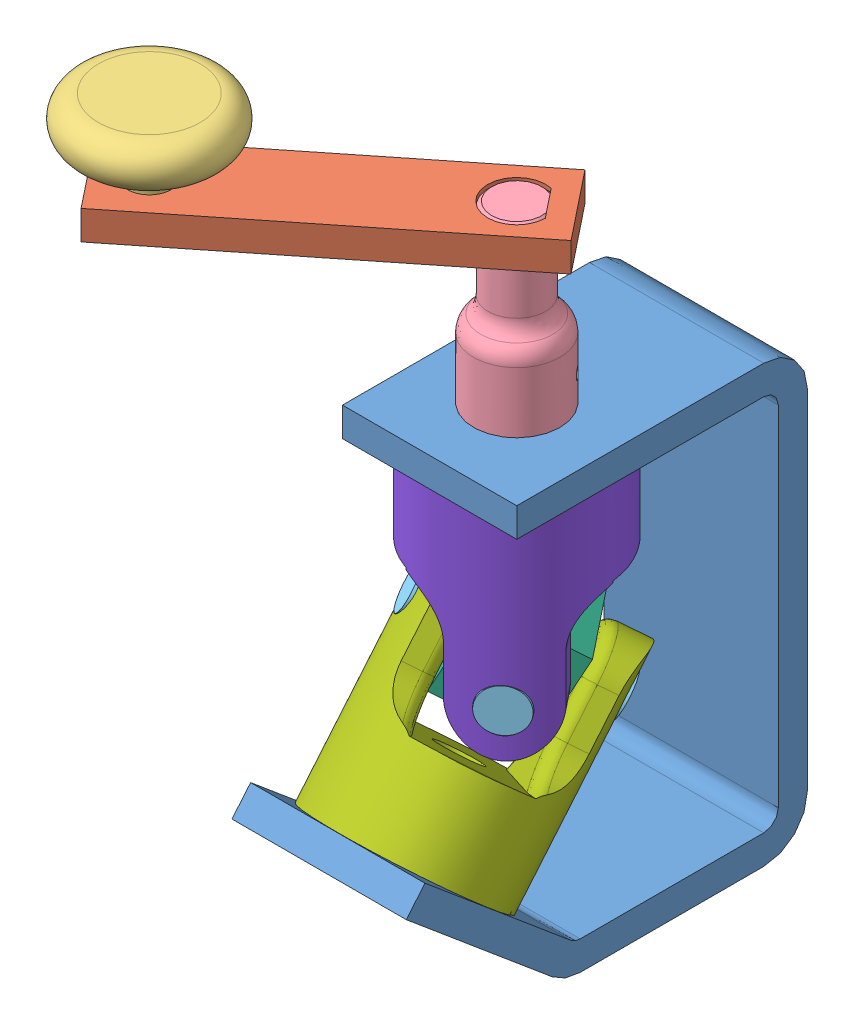
SolidWorks assembly Złożenie1, configuration Domyślna. Lengths in mm.
Overall size (90.07 149.72 98.46).
10 component instances, 8 part files, 21 mates.
Components (placement in the parent):
- bracket-1: bracket [Default] at origin size (38.1 95.25 87.65)
- crank-arm-1: crank-arm [Default] at (-58.0994 121.15 72.1697) x (0.782417 0 -0.622755) z (0.622755 0 0.782417) size (76.2 6.35 19.05)
- crank-knob-1: crank-knob [Default] at (-44.7151 121.15 73.6904) x (0.984418 0 0.175846) z (-0.175846 0 0.984418) size (31.75 22.23 31.75)
- crank-shaft-1: crank-shaft [Default] at (0 89.4 38.1) x (0.782417 0 -0.622755) z (0.622755 0 0.782417) size (18.92 38.1 18.92)
- pin-1: pin [SHORT] at (-3.9545 44.45 33.1317) x (-0.728779 -0.363881 0.580062) z (-0.622755 0 -0.782417) size (9.4 9.4 12.7)
- spider-4: spider [Default] at (0 44.45 38.1) x (-0.693447 0.463133 0.551941) z (-0.622755 0 -0.782417) size (19.05 19.05 19.05)
- Yoke_female-1: Yoke_female [Default] at (0 51.7466 31.9774) x (0.720507 0.445739 0.531211) z (0.693447 -0.463133 -0.551941) size (38.1 47.62 38.1)
- Yoke_male-1: Yoke_male [Default] at (0 34.925 38.1) x (0.782417 0 -0.622755) z (0.622755 0 0.782417) size (38.1 66.67 38.1)
- pin-2: pin [LONG] at (13.2102 35.6273 27.5855) x (0.70373 0.271013 0.656746) z (-0.693447 0.463133 0.551941) size (9.4 9.4 38.1)
- pin-3: pin [SHORT] at (3.9545 44.45 43.0683) x (0.692243 -0.466067 -0.550982) z (0.622755 0 0.782417) size (9.4 9.4 12.7)
Mates (geometry in assembly coordinates):
- Koncentryczne1: concentric anti-aligned: cylinder of crank-arm-1 through (-44.7151 121.15 73.6904) axis (0 1 0) radius 2.3813; cylinder of crank-knob-1 through (-44.7151 121.15 73.6904) axis (0 -1 0) radius 2.286
- Wspólnie1: coincident anti-aligned: plane of crank-arm-1 through (13.3843 127.5 39.6208) normal (0 1 0); plane of crank-knob-1 through (-40.0268 127.5 74.5279) normal (0 -1 0)
- Koncentryczne2: concentric anti-aligned: cylinder of crank-arm-1 through (0 121.15 38.1) axis (0 1 0) radius 6.35; cylinder of crank-shaft-1 through (0 127.5 38.1) axis (0 -1 0) radius 6.2865
- Wspólnie2: coincident anti-aligned: plane of crank-arm-1 through (1.3025 121.15 31.885) normal (-0.782417 0 0.622755); plane of crank-shaft-1 through (6.2863 121.15 38.1466) normal (0.782417 0 -0.622755)
- Wspólnie3: coincident aligned: plane of crank-arm-1 through (13.3843 127.5 39.6208) normal (0 1 0); plane of crank-shaft-1 through (0 127.5 38.1) normal (0 1 0)
- Koncentryczne3: concentric anti-aligned: cylinder of bracket-1 through (0 -6.351 38.1) axis (0 1 0) radius 6.35; cylinder of Yoke_male-1 through (0 101.6 38.1) axis (0 -1 0) radius 6.35
- Wspólnie4: coincident anti-aligned: plane of bracket-1 through (19.05 82.55 3.175) normal (0 -1 0); plane of Yoke_male-1 through (0 82.55 38.1) normal (0 1 0)
- Koncentryczne4: concentric aligned: cylinder of crank-shaft-1 through (0 102.1 38.1) axis (0 -1 0) radius 6.477; cylinder of Yoke_male-1 through (0 101.6 38.1) axis (0 -1 0) radius 6.35
- Równolegle2: parallel anti-aligned: plane of crank-shaft-1 through (6.471 102.1 38.3786) normal (-0.782417 0 0.622755); plane of Yoke_male-1 through (6.3419 88.9 38.4204) normal (0.782417 0 -0.622755)
- Odległość1: distance = 0.5 mm anti-aligned: plane of crank-shaft-1 through (0 89.4 38.1) normal (0 -1 0); plane of bracket-1 through (19.05 88.9 3.175) normal (0 1 0)
- Koncentryczne5: concentric aligned: cylinder of spider-4 through (-5.9317 44.45 30.6475) axis (0.622755 0 0.782417) radius 4.7625; cylinder of Yoke_male-1 through (-11.8635 44.45 23.195) axis (0.622755 0 0.782417) radius 4.7625
- Szerokość1: width anti-aligned: plane of spider-4 through (-2.7782 31.5968 28.1374) normal (-0.622755 0 -0.782417); plane of spider-4 through (9.0853 31.5968 43.0425) normal (0.622755 0 0.782417); plane of Yoke_male-1 through (-21.2322 64.0702 42.0141) normal (0.622755 0 0.782417); plane of Yoke_male-1 through (-8.5779 27.4697 57.9128) normal (-0.622755 0 -0.782417)
- Szerokość2: width: plane of spider-4 through (-9.0853 57.3032 33.1575) normal (-0.693447 0.463133 0.551941); plane of spider-4 through (-2.7782 31.5968 28.1374) normal (0.693447 -0.463133 -0.551941); cylinder of Yoke_female-1 through (0 51.7466 31.9774) axis (0 -0.766044 0.642788) radius 4.7625
- Koncentryczne6: concentric anti-aligned: cylinder of spider-4 through (6.6051 40.0387 32.8428) axis (-0.693447 0.463133 0.551941) radius 4.7625; cylinder of Yoke_female-1 through (-13.2102 53.2727 48.6145) axis (0.693447 -0.463133 -0.551941) radius 4.7625
- Równolegle3: parallel anti-aligned: plane of bracket-1 through (19.05 27.4943 77.2165) normal (0 0.766044 -0.642788); plane of Yoke_female-1 through (0 15.2637 62.5902) normal (0 -0.766044 0.642788)
- Koncentryczne7: concentric aligned: cylinder of Yoke_female-1 through (-13.2102 53.2727 48.6145) axis (0.693447 -0.463133 -0.551941) radius 4.7625; cylinder of pin-2 through (-13.2102 53.2727 48.6145) axis (0.693447 -0.463133 -0.551941) radius 4.699
- Stycznie1: tangent aligned: cylinder of Yoke_female-1 through (0 15.2637 62.5902) axis (0 0.766044 -0.642788) radius 19.05; plane of pin-2 through (-13.2102 53.2727 48.6145) normal (-0.693447 0.463133 0.551941)
- Koncentryczne8: concentric aligned: cylinder of pin-1 through (-11.8635 44.45 23.195) axis (0.622755 0 0.782417) radius 4.699; cylinder of Yoke_male-1 through (-11.8635 44.45 23.195) axis (0.622755 0 0.782417) radius 4.7625
- Stycznie2: tangent aligned: plane of pin-1 through (-11.8635 44.45 23.195) normal (-0.622755 0 -0.782417); cylinder of Yoke_male-1 through (0 82.55 38.1) axis (0 -1 0) radius 19.05
- Koncentryczne9: concentric anti-aligned: cylinder of Yoke_male-1 through (-11.8635 44.45 23.195) axis (0.622755 0 0.782417) radius 4.7625; cylinder of pin-3 through (11.8635 44.45 53.005) axis (-0.622755 0 -0.782417) radius 4.699
- Stycznie3: tangent aligned: cylinder of Yoke_male-1 through (0 82.55 38.1) axis (0 -1 0) radius 19.05; plane of pin-3 through (11.8635 44.45 53.005) normal (0.622755 0 0.782417)
